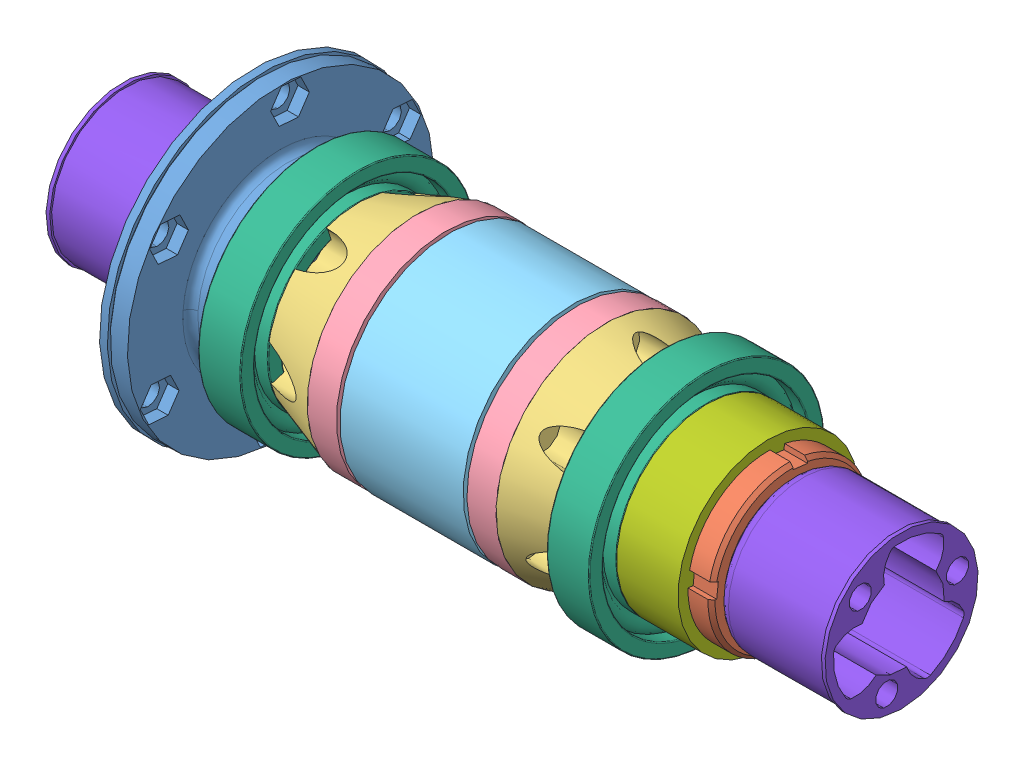
SolidWorks assembly 2012_Differental_Assembly_101411, configuration Default. Lengths in mm.
Overall size (330.87 228.94 229.07).
15 component instances, 9 part files, 7 mates.
Components (placement in the parent):
- quaife-1: quaife [Default] at origin size (238.24 140.51 140.51)
  - DAA107x-1: DAA107x [Default] at (110.5343 226.8851 124.6281) x (1 0 0) z (0 0.069526 0.99758) size (40.89 131.67 131.67)
  - DAA104-1: DAA104 [Default] at (-111.7408 245.6703 -81.5787) x (-1 0 0) z (0 0.248643 -0.968595) size (10 67.91 67.91)
  - DAA104-2: DAA104 [Default] at (111.7408 232.0553 114.7141) x (1 0 0) z (0 0.11254 0.993647) size (10 67.91 67.91)
  - daa101-1: daa101 [Default] at (110.5343 257.6984 24.5051) x (1 0 0) z (0 0.459188 0.888339) size (78.03 93.22 93.22)
  - DAA102-1: DAA102 [Default] at (-110.5343 -50.3551 -253.916) x (-1 0 0) z (0 -0.930099 -0.367309) size (12.38 93.22 93.22)
  - DAA106-1: DAA106 [Default] at (110.4218 -132.5606 222.3436) x (1 0 0) z (0 -0.999413 0.034263) size (62.48 93.22 93.22)
  - daa101-2: daa101 [Default] at (-110.5343 -46.3671 -254.6745) x (-1 0 0) z (0 -0.924225 -0.381849) size (78.03 93.22 93.22)
  - DAA102-2: DAA102 [Default] at (110.5343 -126.8259 -225.6638) x (1 0 0) z (0 0.467879 -0.883793) size (12.38 93.22 93.22)
  - DAA103-1: DAA103 [Default] at (74.1299 -3.2907 140.0622) x (1 0 0) z (0 -0.023488 0.999724) size (18 100 100)
  - DAA103-2: DAA103 [Default] at (-73.9089 21.8066 138.3933) x (1 0 0) z (0 0.155649 0.987812) size (18 100 100)
  - DAA107y-1: DAA107y [Default] at (-110.5343 -64.4395 -250.712) x (-1 0 0) z (0 -0.949139 -0.314858) size (40.89 76.67 76.67)
- Taylor_02004131-1: Taylor_02004131 [Default] at (-165.135 0 0) x (1 0 0) z (0 -0.23529 0.971925) size (142.88 65.07 65.07)
- Taylor_02004131-2: Taylor_02004131 [Default] at (165.735 0 0) x (-1 0 0) z (0 -0.965044 -0.262089) size (142.88 65.07 65.07)
- Sprocket-1: Sprocket [Big Sprocket] at (-113.9444 0 0) x (0 -0.069526 -0.99758) z (1 0 0) size (214.67 214.54 10.23) (hidden)
Mates (geometry in assembly coordinates):
- Concentric1: concentric anti-aligned: cylinder of quaife-1/DAA106-1 through (-26.2237 0 0) axis (1 0 0) radius 46.609; cylinder of Taylor_02004131-1 through (-196.4231 0 0) axis (-1 0 0) radius 31.75
- Concentric2: concentric aligned: cylinder of quaife-1/DAA106-1 through (-26.2237 0 0) axis (1 0 0) radius 46.609; cylinder of Taylor_02004131-2 through (197.0231 0 0) axis (1 0 0) radius 31.75
- Distance1: distance = 6.95 mm anti-aligned: plane of quaife-1/daa101-1 through (-118.11 -33.138 -10.5536) normal (-1 0 0); plane of Taylor_02004131-1 through (-111.16 6.0361 -24.9338) normal (1 0 0)
- Distance2: distance = 6.35 mm anti-aligned: plane of quaife-1/daa101-2 through (118.11 13.338 32.1186) normal (1 0 0); plane of Taylor_02004131-2 through (111.76 24.7572 6.7236) normal (-1 0 0)
- Coincident3: coincident anti-aligned: plane of quaife-1/DAA107x-1 through (-109.1184 -71.0979 -61.8333) normal (-1 0 0); plane of Sprocket-1 through (-109.1184 0 0) normal (1 0 0)
- Concentric3: concentric anti-aligned: cylinder of Taylor_02004131-1 through (-196.4231 0 0) axis (-1 0 0) radius 31.75; cylinder of Sprocket-1 through (-119.0605 0 0) axis (1 0 0) radius 45.72
- Concentric4: concentric anti-aligned: cylinder of quaife-1/DAA107x-1 through (-102.8319 31.9469 47.3869) axis (-1 0 0) radius 4.7625; cylinder of Sprocket-1 through (-119.0605 31.9469 47.3869) axis (1 0 0) radius 4.7625
